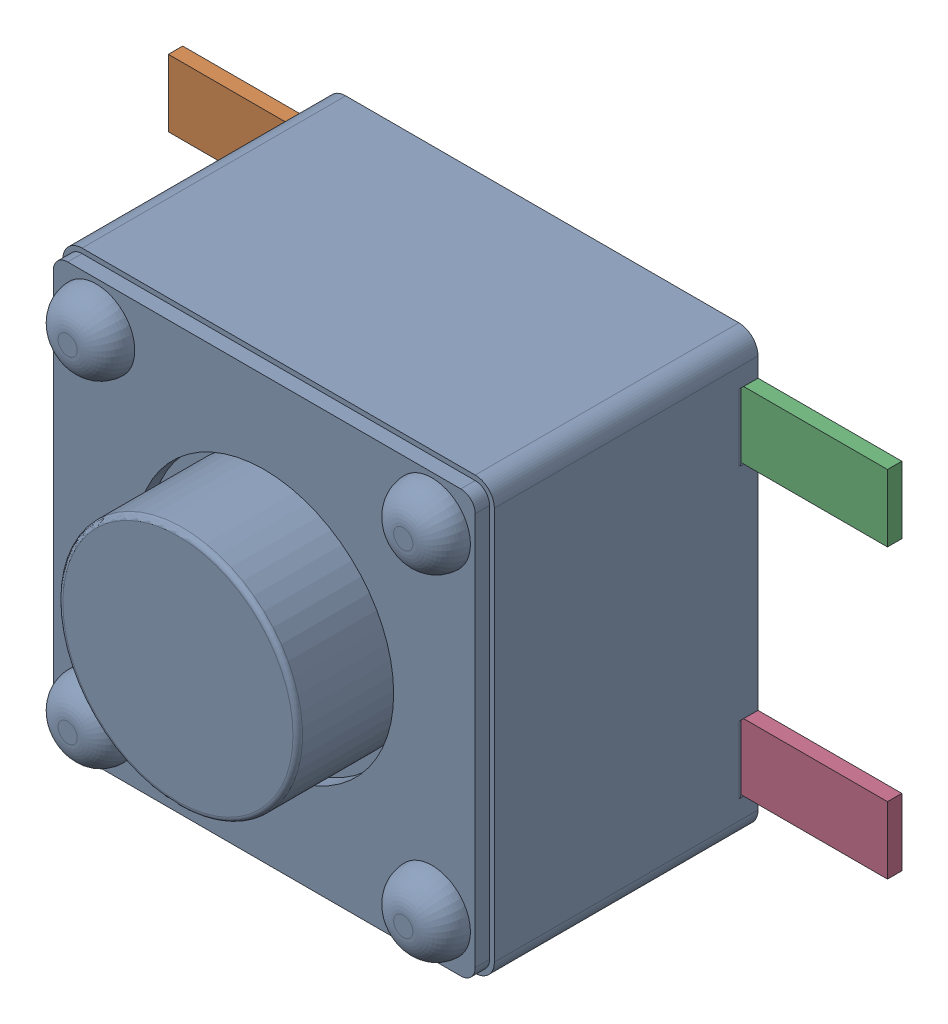
SolidWorks assembly S1, configuration Standard. Lengths in mm.
Overall size (7.5 4.5 3.8).
6 component instances, 5 part files, 0 mates.
Components (placement in the parent):
- 430181038816-1: 430181038816 [Standard] at (-13.9849 -14.7149 0.01) x (1 0 0) z (0 0 1) size (7.5 4.5 3.8)
  - housing_2-1: housing_2 [Standard] at origin size (4.5 4.5 3.8)
  - pins-1: pins [Standard] at origin size (1.8 0.7 0.15)
  - pins_2-1: pins_2 [Standard] at origin size (1.8 0.7 0.15)
  - pins_3-1: pins_3 [Standard] at origin size (1.8 0.7 0.15)
  - pins_4-1: pins_4 [Standard] at origin size (1.8 0.7 0.15)
